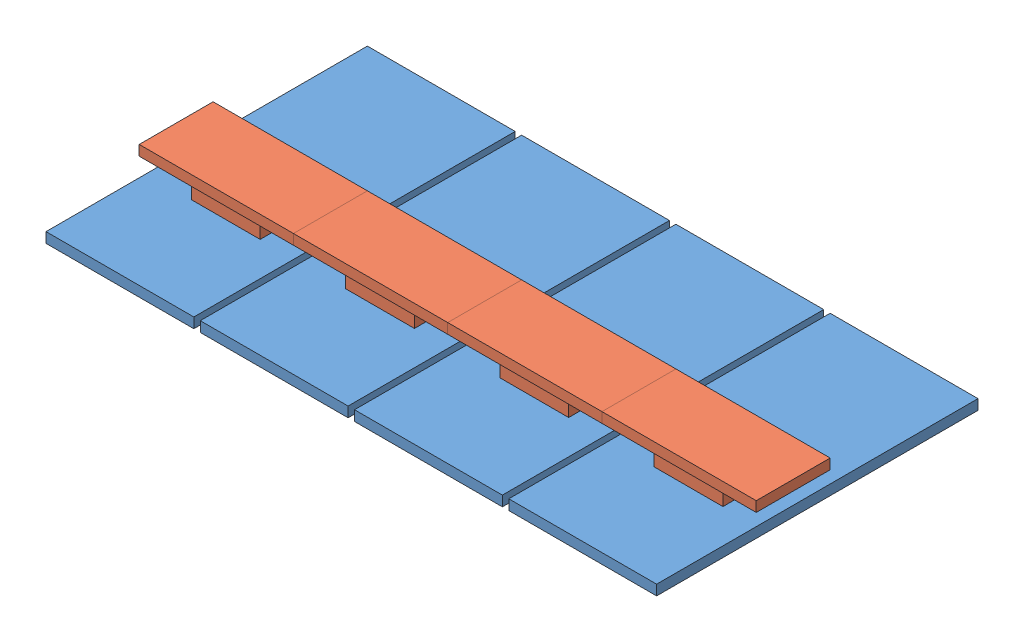
SolidWorks assembly IRS3_DC.4, configuration Default. Lengths in mm.
Overall size (95 4 50).
20 component instances, 3 part files, 0 mates.
Components (placement in the parent):
- IRS3_DC-1: IRS3_DC [Default] at origin size (23 4 50)
  - IRS3_DC.revA-1: IRS3_DC.revA [Default] at origin size (23 1.59 50)
  - IRS3_DC.heatsink-2: IRS3_DC.heatsink [Default] at origin size (10.7 4 10.7)
  - 1206.inductor-1: 1206.inductor [Default] at (20 1.5875 -24.96) size (1.82 1.82 3.21)
  - 1206.inductor-2: 1206.inductor [Default] at (4.64 1.5875 -24.92) size (1.82 1.82 3.21)
- IRS3_DC-2: IRS3_DC [Default] at (24 0 0) size (23 4 50)
  - IRS3_DC.revA-1: IRS3_DC.revA [Default] at origin size (23 1.59 50)
  - IRS3_DC.heatsink-2: IRS3_DC.heatsink [Default] at origin size (10.7 4 10.7)
  - 1206.inductor-1: 1206.inductor [Default] at (20 1.5875 -24.96) size (1.82 1.82 3.21)
  - 1206.inductor-2: 1206.inductor [Default] at (4.64 1.5875 -24.92) size (1.82 1.82 3.21)
- IRS3_DC-3: IRS3_DC [Default] at (48 0 0) size (23 4 50)
  - IRS3_DC.revA-1: IRS3_DC.revA [Default] at origin size (23 1.59 50)
  - IRS3_DC.heatsink-2: IRS3_DC.heatsink [Default] at origin size (10.7 4 10.7)
  - 1206.inductor-1: 1206.inductor [Default] at (20 1.5875 -24.96) size (1.82 1.82 3.21)
  - 1206.inductor-2: 1206.inductor [Default] at (4.64 1.5875 -24.92) size (1.82 1.82 3.21)
- IRS3_DC-4: IRS3_DC [Default] at (72 0 0) size (23 4 50)
  - IRS3_DC.revA-1: IRS3_DC.revA [Default] at origin size (23 1.59 50)
  - IRS3_DC.heatsink-2: IRS3_DC.heatsink [Default] at origin size (10.7 4 10.7)
  - 1206.inductor-1: 1206.inductor [Default] at (20 1.5875 -24.96) size (1.82 1.82 3.21)
  - 1206.inductor-2: 1206.inductor [Default] at (4.64 1.5875 -24.92) size (1.82 1.82 3.21)
